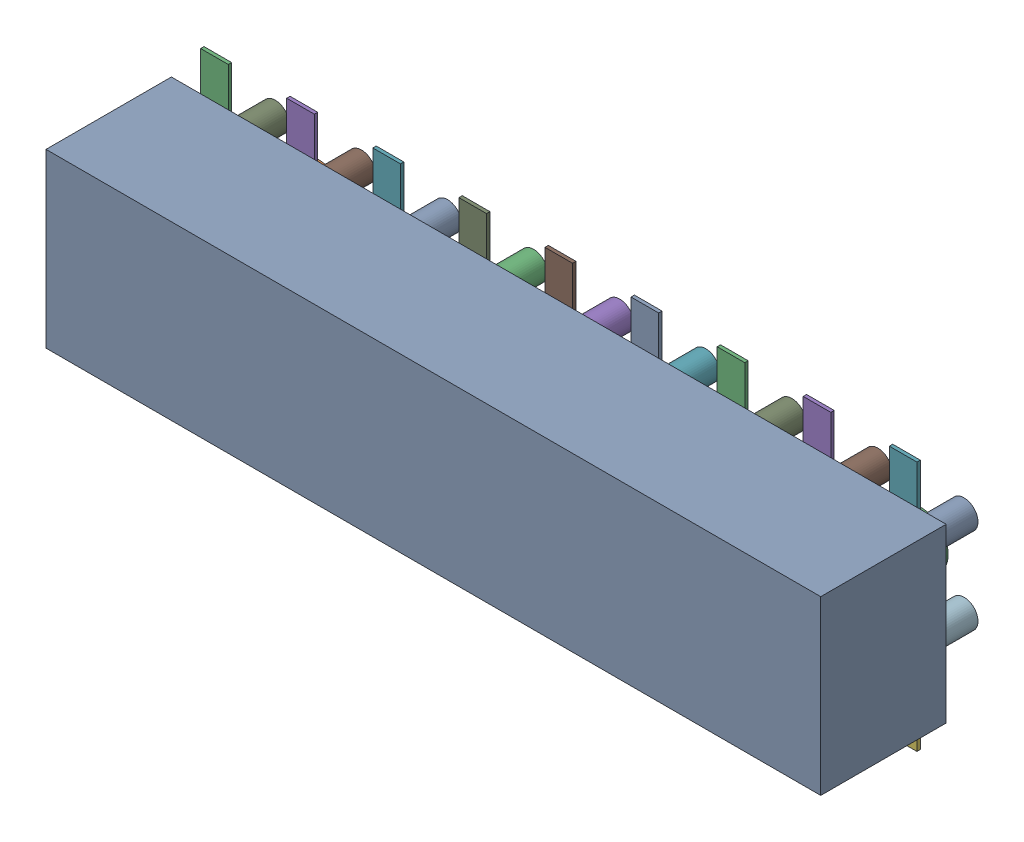
SolidWorks assembly J1, configuration Predeterminado. Lengths in mm.
Overall size (22.86 7.4 5.5).
43 component instances, 39 part files, 0 mates.
Components (placement in the parent):
- Open CASCADE STEP translator 6.8 1.2.1-1: Open CASCADE STEP translator 6.8 1.2.1 [Predeterminado] at origin size (22.86 7.4 5.5)
  - Body_1-1: Body_1 [Predeterminado] at origin size (22.86 7.4 5.5)
    - =_[0_1_1_2]-1: =_[0_1_1_2] [Predeterminado] at (0 0 0.1) size (22.86 5.08 3.7)
    - =_[0_1_1_3]-1: =_[0_1_1_3] [Predeterminado] at origin size (21.14 7.4 0.1)
      - SOLID-1: SOLID [Predeterminado] at origin size (0.82 1.58 0.1)
      - SOLID_2-1: SOLID_2 [Predeterminado] at origin size (0.82 1.58 0.1)
      - SOLID_3-1: SOLID_3 [Predeterminado] at origin size (0.82 1.58 0.1)
      - SOLID_4-1: SOLID_4 [Predeterminado] at origin size (0.82 1.58 0.1)
      - SOLID_5-1: SOLID_5 [Predeterminado] at origin size (0.82 1.58 0.1)
      - SOLID_6-1: SOLID_6 [Predeterminado] at origin size (0.82 1.58 0.1)
      - SOLID_7-1: SOLID_7 [Predeterminado] at origin size (0.82 1.58 0.1)
      - SOLID_8-1: SOLID_8 [Predeterminado] at origin size (0.82 1.58 0.1)
      - SOLID_9-1: SOLID_9 [Predeterminado] at origin size (0.82 1.58 0.1)
      - SOLID_10-1: SOLID_10 [Predeterminado] at origin size (0.82 1.58 0.1)
      - SOLID_11-1: SOLID_11 [Predeterminado] at origin size (0.82 1.58 0.1)
      - SOLID_12-1: SOLID_12 [Predeterminado] at origin size (0.82 1.58 0.1)
      - SOLID_13-1: SOLID_13 [Predeterminado] at origin size (0.82 1.58 0.1)
      - SOLID_14-1: SOLID_14 [Predeterminado] at origin size (0.82 1.58 0.1)
      - SOLID_15-1: SOLID_15 [Predeterminado] at origin size (0.82 1.58 0.1)
      - SOLID_16-1: SOLID_16 [Predeterminado] at origin size (0.82 1.58 0.1)
      - SOLID_17-1: SOLID_17 [Predeterminado] at origin size (0.82 1.58 0.1)
      - SOLID_18-1: SOLID_18 [Predeterminado] at origin size (0.82 1.58 0.1)
    - =_[0_1_1_4]-1: =_[0_1_1_4] [Predeterminado] at origin size (21.14 3.36 1.8)
      - SOLID_19-1: SOLID_19 [Predeterminado] at origin size (0.82 0.82 1.8)
      - SOLID_20-1: SOLID_20 [Predeterminado] at origin size (0.82 0.82 1.8)
      - SOLID_21-1: SOLID_21 [Predeterminado] at origin size (0.82 0.82 1.8)
      - SOLID_22-1: SOLID_22 [Predeterminado] at origin size (0.82 0.82 1.8)
      - SOLID_23-1: SOLID_23 [Predeterminado] at origin size (0.82 0.82 1.8)
      - SOLID_24-1: SOLID_24 [Predeterminado] at origin size (0.82 0.82 1.8)
      - SOLID_25-1: SOLID_25 [Predeterminado] at origin size (0.82 0.82 1.8)
      - SOLID_26-1: SOLID_26 [Predeterminado] at origin size (0.82 0.82 1.8)
      - SOLID_27-1: SOLID_27 [Predeterminado] at origin size (0.82 0.82 1.8)
      - SOLID_28-1: SOLID_28 [Predeterminado] at origin size (0.82 0.82 1.8)
      - SOLID_29-1: SOLID_29 [Predeterminado] at origin size (0.82 0.82 1.8)
      - SOLID_30-1: SOLID_30 [Predeterminado] at origin size (0.82 0.82 1.8)
      - SOLID_31-1: SOLID_31 [Predeterminado] at origin size (0.82 0.82 1.8)
      - SOLID_32-1: SOLID_32 [Predeterminado] at origin size (0.82 0.82 1.8)
      - SOLID_33-1: SOLID_33 [Predeterminado] at origin size (0.82 0.82 1.8)
      - SOLID_34-1: SOLID_34 [Predeterminado] at origin size (0.82 0.82 1.8)
      - SOLID_35-1: SOLID_35 [Predeterminado] at origin size (0.82 0.82 1.8)
      - SOLID_36-1: SOLID_36 [Predeterminado] at origin size (0.82 0.82 1.8)
      - SOLID_37-1: SOLID_37 [Predeterminado] at origin size (1.6 1.6 1.8)
      - SOLID_38-1: SOLID_38 [Predeterminado] at origin size (1.6 1.6 1.8)
